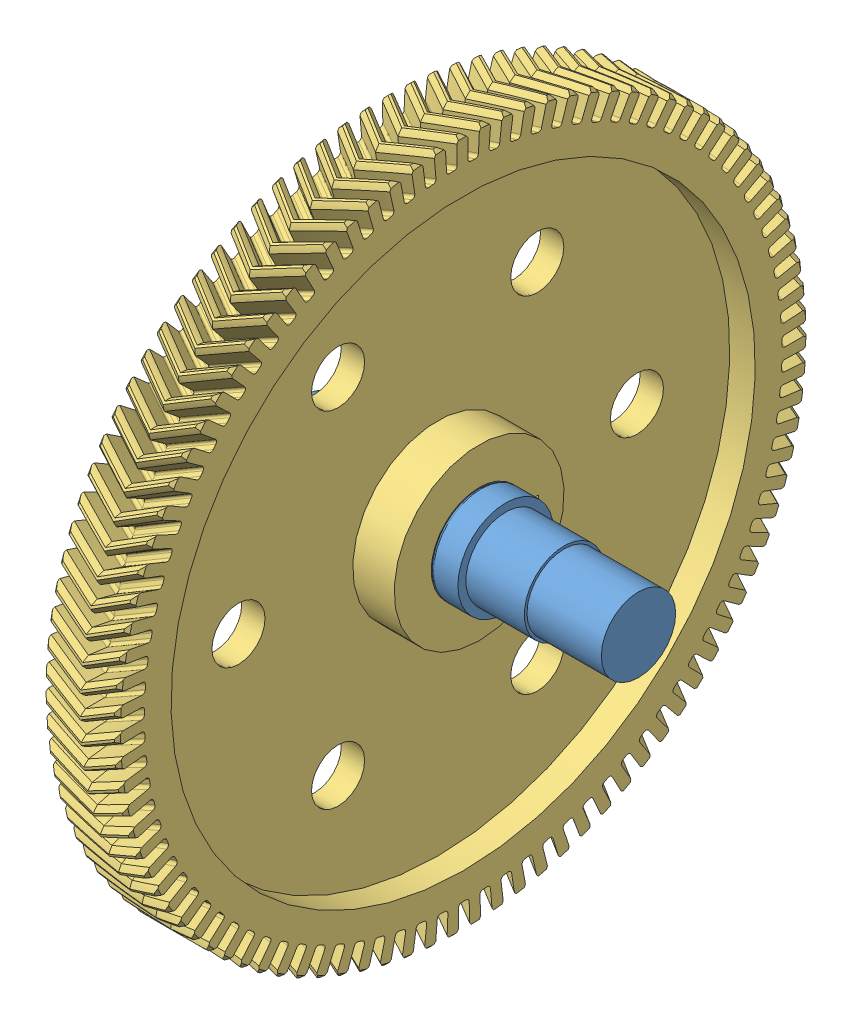
SolidWorks assembly Gear shaft assem, configuration Default. Lengths in mm.
Overall size (315 651.09 651.14).
3 component instances, 3 part files, 6 mates.
Components (placement in the parent):
- Gear Shaft-1: Gear Shaft [Default] at (-151.5806 1.5388 -4.169) size (315 120 120)
- gear key-1: gear key [Default] at (-72.5806 1.5388 -49.169) x (0 -1 0) z (1 0 0) size (22 22 70)
- gear-1: gear [Default] at (-36.5806 1.5388 -4.169) x (-1 0 0) z (0 -1 0) size (100 651.14 651.09)
Mates (geometry in assembly coordinates):
- Coincident2: coincident anti-aligned: plane of Gear Shaft-1 through (-81.5806 12.5388 -38.169) normal (0 0 -1); plane of gear key-1 through (-2.5806 -9.4612 -38.169) normal (0 0 1)
- Coincident3: coincident anti-aligned: line of Gear Shaft-1 through (-70.5806 -9.4612 -38.169) axis (1 0 0); line of gear key-1 through (-2.5806 -9.4612 -38.169) axis (-1 0 0)
- Coincident4: coincident aligned: line of Gear Shaft-1 through (-2.5806 -9.4612 -38.169) axis (0 0 -1); line of gear key-1 through (-2.5806 -9.4612 -38.169) axis (0 0 -1)
- Coincident5: coincident anti-aligned: plane of gear key-1 through (-2.5806 -9.4612 -60.169) normal (0 0 -1); plane of gear-1 through (-86.5816 12.5388 -60.169) normal (0 0 1)
- Concentric1: concentric aligned: cylinder of Gear Shaft-1 through (163.4194 1.5388 -4.169) axis (1 0 0) radius 45; cylinder of gear-1 through (-86.5816 1.5388 -4.169) axis (1 0 0) radius 45
- Coincident6: coincident anti-aligned: plane of Gear Shaft-1 through (-86.5806 1.5388 -64.169) normal (1 0 0); plane of gear-1 through (-86.5806 1.5388 -4.169) normal (-1 0 0)
